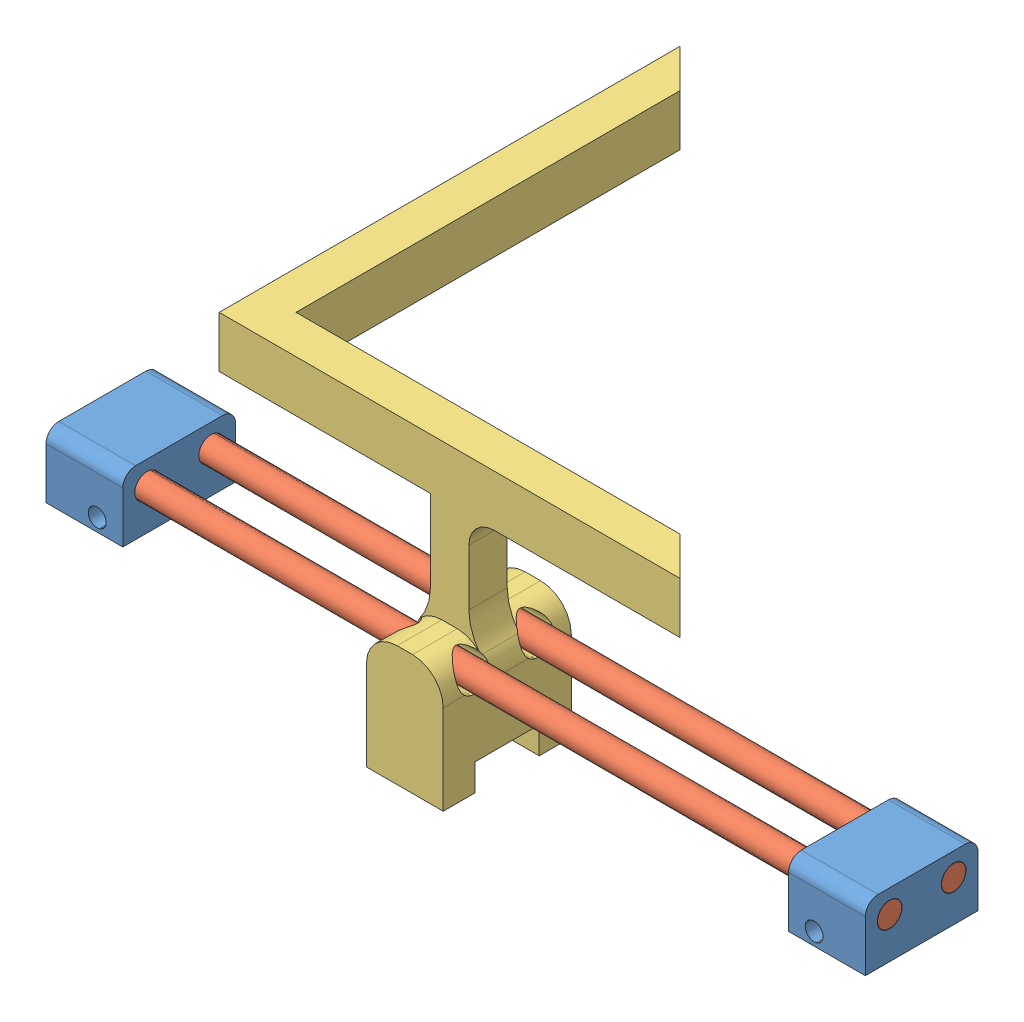
SolidWorks assembly L Pusher subassembly 2, configuration Default. Lengths in mm.
Overall size (160 53.75 98.75).
5 component instances, 3 part files, 10 mates.
Components (placement in the parent):
- Dowel Holder (003)-2: Dowel Holder (003) [Default] at (-95.252 -0.7194 44.5804) x (0 0 -1) z (1 0 0) size (22 12.5 15)
- Dowel Holder (003)-3: Dowel Holder (003) [Default] at (64.748 -0.7194 44.5804) x (0 0 1) z (-1 0 0) size (22 12.5 15)
- dowel-1: dowel [Default] at (-95.252 19.7806 50.8304) size (160 4.75 4.75)
- dowel-2: dowel [Default] at (-95.252 19.7806 38.3304) size (160 4.75 4.75)
- S2_Mirrored Pusher Piece L Pusher-1: S2_Mirrored Pusher Piece L Pusher [Default] at (-14.9563 69.1616 -18.3117) size (90 53.75 98.75)
Mates (geometry in assembly coordinates):
- Concentric1: concentric aligned: cylinder of Dowel Holder (003)-2 through (-80.252 19.7806 50.8304) axis (-1 0 0) radius 2.425; cylinder of dowel-1 through (64.748 19.7806 50.8304) axis (-1 0 0) radius 2.375
- Concentric2: concentric anti-aligned: cylinder of Dowel Holder (003)-3 through (49.748 19.7806 50.8304) axis (1 0 0) radius 2.425; cylinder of dowel-1 through (64.748 19.7806 50.8304) axis (-1 0 0) radius 2.375
- Concentric3: concentric aligned: cylinder of Dowel Holder (003)-2 through (-80.252 19.7806 38.3304) axis (-1 0 0) radius 2.425; cylinder of dowel-2 through (64.748 19.7806 38.3304) axis (-1 0 0) radius 2.375
- Concentric4: concentric anti-aligned: cylinder of Dowel Holder (003)-3 through (49.748 19.7806 38.3304) axis (1 0 0) radius 2.425; cylinder of dowel-2 through (64.748 19.7806 38.3304) axis (-1 0 0) radius 2.375
- Concentric5: concentric aligned: cylinder of dowel-2 through (64.748 19.7806 38.3304) axis (-1 0 0) radius 2.375; cylinder of S2_Mirrored Pusher Piece L Pusher-1 through (-16.1816 19.7806 38.3304) axis (-1 0 0) radius 3.175
- Concentric6: concentric aligned: cylinder of dowel-1 through (64.748 19.7806 50.8304) axis (-1 0 0) radius 2.375; cylinder of S2_Mirrored Pusher Piece L Pusher-1 through (-16.1816 19.7806 50.8304) axis (-1 0 0) radius 3.175
- Coincident1: coincident aligned: plane of Dowel Holder (003)-3 through (64.748 -0.7194 44.5804) normal (1 0 0); plane of dowel-1 through (64.748 19.7806 50.8304) normal (1 0 0)
- Coincident2: coincident aligned: plane of Dowel Holder (003)-3 through (64.748 -0.7194 44.5804) normal (1 0 0); plane of dowel-2 through (64.748 19.7806 38.3304) normal (1 0 0)
- Coincident3: coincident aligned: plane of Dowel Holder (003)-2 through (-95.252 -0.7194 44.5804) normal (-1 0 0); plane of dowel-1 through (-95.252 19.7806 50.8304) normal (-1 0 0)
- Coincident4: coincident aligned: plane of Dowel Holder (003)-2 through (-95.252 -0.7194 44.5804) normal (-1 0 0); plane of dowel-2 through (-95.252 19.7806 38.3304) normal (-1 0 0)
